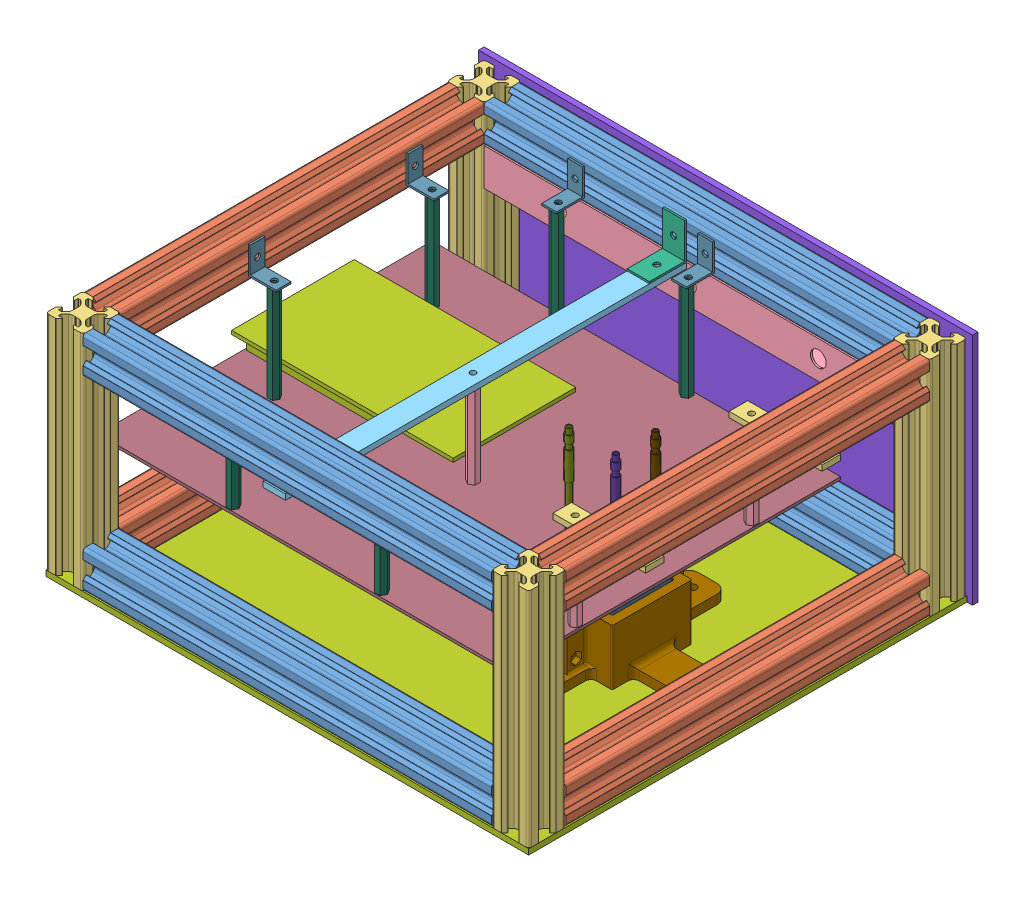
SolidWorks assembly Электродный блок, configuration По умолчанию. Lengths in mm.
Overall size (266 126 239).
75 component instances, 36 part files, 131 mates.
Components (placement in the parent):
- профиль x1-1: профиль x1 [00] at (0 10 10) x (0 0 1) z (-1 0 0) size (20 20 220)
- профиль z1-1: профиль z1 [00] at (10 10 20) size (20 20 196)
- профиль y-1: профиль y [00] at (10 120 10) x (1 0 0) z (0 -1 0) size (20 20 120)
- уголок 8-1: уголок 8 [По умолчанию] at (-220 80 20) x (0 0 -1) z (0 -1 0) size (20 220 20)
- уголок 10-1: уголок 10 [По умолчанию] at (-220 81 19) size (20 19 19)
- уголок 11-2: уголок 11 [По умолчанию] at (0 81 19) x (0 0 -1) z (1 0 0) size (19 19 20)
- Крышка ЭБ-1: Крышка ЭБ [По умолчанию] at (-15.6691 90 -0.0645) size (260 3 236) (hidden)
- Днище ЭБ-1: Днище ЭБ [По умолчанию] at (-21.0208 0 19.9277) size (260 3 236)
- Передняя панель ЭБ-1: Передняя панель ЭБ [По умолчанию] at origin size (3 126 236) (hidden)
- Задняя панель ЭБ-1: Задняя панель ЭБ [По умолчанию] at origin size (3 126 236) (hidden)
- Левая панель ЭБ-1: Левая панель ЭБ [По умолчанию] at origin size (266 126 3)
- Правая панель ЭБ-1: Правая панель ЭБ [По умолчанию] at origin size (266 126 3) (hidden)
- профиль x1-6: профиль x1 [00] at (-220 10 226) x (0 0 -1) z (1 0 0) size (20 20 220)
- профиль y-5: профиль y [00] at (10 0 226) x (1 0 0) z (0 1 0) size (20 20 120)
- профиль z1-5: профиль z1 [00] at (-230 10 216) x (-1 0 0) z (0 0 -1) size (20 20 196)
- профиль y-6: профиль y [00] at (-230 120 226) x (-1 0 0) z (0 -1 0) size (20 20 120)
- профиль y-7: профиль y [00] at (-230 0 10) x (-1 0 0) z (0 1 0) size (20 20 120)
- профиль x1-7: профиль x1 [00] at (-220 110 10) x (0 0 1) z (1 0 0) size (20 20 220)
- профиль z1-6: профиль z1 [00] at (10 110 216) x (1 0 0) z (0 0 -1) size (20 20 196)
- профиль x1-8: профиль x1 [00] at (0 110 226) x (0 0 -1) z (-1 0 0) size (20 20 220)
- профиль z1-7: профиль z1 [00] at (-230 110 20) x (-1 0 0) z (0 0 1) size (20 20 196)
- Кювета с держателем-3: Кювета с держателем [Default] at (-69.5 5 134.5) x (1 0 0) z (0 1 0) size (74.5 103 46.5)
  - Держатель-1: Держатель [Default] at origin size (74.5 103 30)
  - Квадратная кювета-1: Квадратная кювета [Default] at (-0.25 33.25 0) x (0 -1 0) z (-1 0 0) size (33.5 39.5 33.5)
  - Зажим квадратный-1: Зажим квадратный [По умолчанию] at (-5 38 0) x (0 -1 0) z (-1 0 0) size (63 25 19.5)
  - Клипса-1: Клипса [Default] at origin size (7.5 15 10)
- Электродная плата-1: Электродная плата [Default] at (-240 48 208) size (220 12.5 180)
- Уголок крепления платы-1: Уголок крепления платы [По умолчанию] at (-174 102.5 20) x (0 1 0) z (1 0 0) size (15 15 8)
- Уголок крепления платы-2: Уголок крепления платы [По умолчанию] at (-104 102.5 20) x (0 1 0) z (1 0 0) size (15 15 8)
- Уголок крепления платы-3: Уголок крепления платы [По умолчанию] at (-220 102.5 62) x (0 1 0) z (0 0 -1) size (15 15 8)
- Стойка крепления платы-1: Стойка крепления платы [По умолчанию] at (-170 49.5 31) size (5 53 5.77)
- Стойка крепления платы-2: Стойка крепления платы [По умолчанию] at (-100 49.5 31) size (5 53 5.77)
- Стойка крепления платы-3: Стойка крепления платы [По умолчанию] at (-210 49.5 58) size (5 53 5.77)
- Крепление цанг-1: Крепление цанг [По умолчанию] at (0 65 143) x (-1 0 0) z (0 0 -1) size (75 55 50) (hidden)
- Цанга залив-1: Цанга залив [По умолчанию] at (-65.6 61.5 128.7) x (0.866025 0 -0.5) z (0.5 0 0.866025) size (12 60 13.86)
  - Цанговый зажим-1: Цанговый зажим [По умолчанию] at origin size (12 28.5 13.86)
    - втулка-1: втулка [По умолчанию] at origin size (9.5 23 9.5) (hidden)
    - цанга-1: цанга [По умолчанию] at (0 13 0) size (6 15.5 6) (hidden)
    - прижимная гайка-1: прижимная гайка [По умолчанию] at (0 16.5 0) x (-1 0 0) z (0 0 -1) size (11 10.5 11) (hidden)
    - фиксирующая гайка-1: фиксирующая гайка [По умолчанию] at (0 11.5 0) x (1 0 0) z (0 -1 0) size (12 13.86 2) (hidden)
  - Игла залив-1: Игла залив [По умолчанию] at (0 -21 0) size (4 60 4)
- Цанга забор-1: Цанга забор [По умолчанию] at (-40.4 61.5 128.7) size (12 72 13.86)
  - Цанговый зажим-1: Цанговый зажим [По умолчанию] at origin size (12 28.5 13.86)
    - втулка-1: втулка [По умолчанию] at origin size (9.5 23 9.5) (hidden)
    - цанга-1: цанга [По умолчанию] at (0 13 0) size (6 15.5 6) (hidden)
    - прижимная гайка-1: прижимная гайка [По умолчанию] at (0 16.5 0) x (-1 0 0) z (0 0 -1) size (11 10.5 11) (hidden)
    - фиксирующая гайка-1: фиксирующая гайка [По умолчанию] at (0 11.5 0) x (1 0 0) z (0 -1 0) size (12 13.86 2) (hidden)
  - Игла забор-1: Игла забор [По умолчанию] at (0 -33 0) size (4 72 4)
- Цанга слив-1: Цанга слив [По умолчанию] at (-40.4 61.5 107.3) size (12 92 13.86)
  - Цанговый зажим-1: Цанговый зажим [По умолчанию] at origin size (12 28.5 13.86)
    - втулка-1: втулка [По умолчанию] at origin size (9.5 23 9.5) (hidden)
    - цанга-1: цанга [По умолчанию] at (0 13 0) size (6 15.5 6) (hidden)
    - прижимная гайка-1: прижимная гайка [По умолчанию] at (0 16.5 0) x (-1 0 0) z (0 0 -1) size (11 10.5 11) (hidden)
    - фиксирующая гайка-1: фиксирующая гайка [По умолчанию] at (0 11.5 0) x (1 0 0) z (0 -1 0) size (12 13.86 2) (hidden)
  - Игла слив1-1: Игла слив1 [По умолчанию] at (0 -53 0) size (4 92 4)
- Электрод-фольга-1: Электрод-фольга [Default] at (-68.25 9 131.75) size (28 39 0.3)
- Электрод-фольга-2: Электрод-фольга [Default] at (-40.25 9 104.25) x (-1 0 0) z (0 0 -1) size (28 39 0.3)
- Иголка-электрод-1: Иголка-электрод [Default] at (-53.25 8.5 125) x (-0.595798 0 0.803134) z (-0.803134 0 -0.595798) size (1.5 39.5 1.5)
- Иголка-электрод-2: Иголка-электрод [Default] at (-53.25 8.5 111) x (-0.595798 0 -0.803134) z (0.803134 0 -0.595798) size (1.5 39.5 1.5)
- Стойка крепления платы-7: Стойка крепления платы [По умолчанию] at (-210 49.5 143) x (0 0 -1) z (1 0 0) size (5 53 5.77)
- Стойка крепления платы-8: Стойка крепления платы [По умолчанию] at (-170 49.5 205) x (0 0 -1) z (1 0 0) size (5 53 5.77)
- Стойка крепления платы-9: Стойка крепления платы [По умолчанию] at (-90 49.5 205) x (0.866025 0 -0.5) z (0.5 0 0.866025) size (5 53 5.77)
- Уголок крепления платы-7: Уголок крепления платы [По умолчанию] at (-220 102.5 147) x (0 1 0) z (0 0 -1) size (15 15 8)
- Уголок крепления платы-8: Уголок крепления платы [По умолчанию] at (-166 102.5 216) x (0 1 0) z (-1 0 0) size (15 15 8)
- Уголок крепления платы-9: Уголок крепления платы [По умолчанию] at (-86 102.5 216) x (0 1 0) z (-1 0 0) size (15 15 8)
- Пластина крпления платы-1: Пластина крпления платы [Default] at (-30 97 78) size (50 3 10)
- Пластина крпления платы-2: Пластина крпления платы [Default] at (-30 97 173) size (50 3 10)
- Стойка крепления платы средняя-1: Стойка крепления платы средняя [По умолчанию] at (-23 49.5 73) size (5 47.5 5.77)
- Стойка крепления платы средняя-2: Стойка крепления платы средняя [По умолчанию] at (-23 49.5 168) size (5 47.5 5.77)
- Пластина крепления центральная-1: Пластина крепления центральная [Default] at (-111 100 20) x (0 0 1) z (0 -1 0) size (216 12 3)
- Уголок крепления 20-1: Уголок крепления 20 [Default] at (-111 100 20) x (0 0 1) z (-1 0 0) size (20 20 12)
- Стойка крепления платы средняя-3: Стойка крепления платы средняя [По умолчанию] at (-117 49.5 129) size (5 47.5 5.77)
- юзб_блок-1: юзб_блок [По умолчанию] at (-240 59.8 136) size (119.3 12.3 66)
- Part2^Электродный блок-1: Part2^Электродный блок [Default] at origin size (65.25 29.5 48.5) (hidden, virtual)
- Part3^Электродный блок-1: Part3^Электродный блок [Default] at origin size (45.7 10.75 39.9) (hidden, virtual)
Mates (geometry in assembly coordinates):
- Совпадение20: coincident anti-aligned: plane of профиль x1-1 through (-220 18.5 0) normal (0 0 -1); plane of assembly through (0 0 0) normal (0 0 1)
- Совпадение21: coincident anti-aligned: plane of профиль x1-1 through (-220 0 1.5) normal (0 -1 0); plane of assembly through (0 0 0) normal (0 1 0)
- Совпадение22: coincident aligned: plane of профиль x1-1 through (0 10.3377 6.25) normal (1 0 0); plane of assembly through (0 0 0) normal (1 0 0)
- Совпадение23: coincident anti-aligned: plane of профиль x1-1 through (0 10.3377 6.25) normal (1 0 0); plane of профиль y-1 through (0 0 5.17) normal (-1 0 0)
- Совпадение24: coincident aligned: plane of профиль x1-1 through (-220 18.5 0) normal (0 0 -1); plane of профиль y-1 through (1.5 0 0) normal (0 0 -1)
- Совпадение25: coincident aligned: plane of профиль x1-1 through (-220 0 1.5) normal (0 -1 0); plane of профиль y-1 through (6.25 0 10.3377) normal (0 -1 0)
- Совпадение26: coincident aligned: plane of профиль z1-1 through (20 1.5 216) normal (1 0 0); plane of профиль y-1 through (20 0 1.5) normal (1 0 0)
- Совпадение27: coincident anti-aligned: plane of профиль z1-1 through (6.25 10.3377 20) normal (0 0 -1); plane of профиль y-1 through (18.5 0 20) normal (0 0 1)
- Совпадение28: coincident aligned: plane of профиль z1-1 through (14.83 0 216) normal (0 -1 0); plane of профиль y-1 through (6.25 0 10.3377) normal (0 -1 0)
- Совпадение62: coincident anti-aligned: plane of профиль y-1 through (0 0 18.5) normal (-1 0 0); plane of уголок 8-1 through (0 80 20) normal (1 0 0)
- Совпадение66: coincident anti-aligned: plane of уголок 8-1 through (0 81 19) normal (0 1 0); plane of уголок 10-1 through (-220 81 19) normal (0 -1 0)
- Совпадение67: coincident anti-aligned: plane of уголок 8-1 through (0 100 19) normal (0 0 -1); plane of уголок 10-1 through (-200 100 19) normal (0 0 1)
- Совпадение68: coincident anti-aligned: plane of уголок 8-1 through (0 100 19) normal (0 0 -1); plane of уголок 11-2 through (0 100 19) normal (0 0 1)
- Совпадение69: coincident anti-aligned: plane of профиль y-1 through (0 0 5.17) normal (-1 0 0); plane of уголок 11-2 through (0 100 -1) normal (1 0 0)
- Совпадение70: coincident anti-aligned: plane of уголок 8-1 through (0 81 19) normal (0 1 0); plane of уголок 11-2 through (0 81 19) normal (0 -1 0)
- Совпадение74: coincident anti-aligned: plane of профиль x1-1 through (-220 0 1.5) normal (0 -1 0); plane of Днище ЭБ-1 through (-21.0208 0 19.9277) normal (0 1 0)
- Совпадение77: coincident aligned: plane of профиль y-6 through (-234.83 0 236) normal (0 0 1); plane of Передняя панель ЭБ-1 through (-243 123 236) normal (0 0 1)
- Совпадение78: coincident aligned: plane of Крышка ЭБ-1 through (-15.6691 123 -0.0645) normal (0 1 0); plane of Передняя панель ЭБ-1 through (-243 123 0) normal (0 1 0)
- Совпадение79: coincident anti-aligned: plane of профиль y-6 through (-240 0 234.5) normal (-1 0 0); plane of Передняя панель ЭБ-1 through (-240 0 0) normal (1 0 0)
- Совпадение81: coincident aligned: plane of Крышка ЭБ-1 through (-15.6691 123 -0.0645) normal (0 1 0); plane of Задняя панель ЭБ-1 through (23 123 0) normal (0 1 0)
- Совпадение83: coincident aligned: plane of Передняя панель ЭБ-1 through (-243 0 0) normal (-1 0 0); plane of Левая панель ЭБ-1 through (-243 123 -3) normal (-1 0 0)
- Совпадение84: coincident aligned: plane of Крышка ЭБ-1 through (-15.6691 123 -0.0645) normal (0 1 0); plane of Левая панель ЭБ-1 through (23 123 -3) normal (0 1 0)
- Совпадение86: coincident aligned: plane of Крышка ЭБ-1 through (-15.6691 123 -0.0645) normal (0 1 0); plane of Правая панель ЭБ-1 through (23 123 239) normal (0 1 0)
- Совпадение87: coincident aligned: plane of Задняя панель ЭБ-1 through (23 0 0) normal (1 0 0); plane of Правая панель ЭБ-1 through (23 -3 239) normal (1 0 0)
- Coincident28: coincident aligned: plane of профиль y-1 through (1.5 0 0) normal (0 0 -1); plane of уголок 8-1 through (0 81 0) normal (0 0 -1)
- Coincident29: coincident anti-aligned: plane of профиль y-7 through (-220 120 5.17) normal (1 0 0); plane of уголок 10-1 through (-220 100 19) normal (-1 0 0)
- Coincident32: coincident aligned: plane of профиль y-1 through (20 0 1.5) normal (1 0 0); plane of Крышка ЭБ-1 through (20 123 0) normal (1 0 0)
- Coincident33: coincident aligned: plane of профиль y-1 through (14.83 0 0) normal (0 0 -1); plane of Крышка ЭБ-1 through (-240 123 0) normal (0 0 -1)
- Coincident34: coincident anti-aligned: plane of профиль y-1 through (6.25 120 10.3377) normal (0 1 0); plane of Крышка ЭБ-1 through (-15.6691 120 -0.0645) normal (0 -1 0)
- Coincident35: coincident aligned: plane of профиль y-1 through (14.83 0 0) normal (0 0 -1); plane of Днище ЭБ-1 through (-240 -3 0) normal (0 0 -1)
- Coincident36: coincident aligned: plane of профиль y-1 through (20 0 1.5) normal (1 0 0); plane of Днище ЭБ-1 through (20 -3 0) normal (1 0 0)
- Coincident37: coincident aligned: plane of профиль y-7 through (-234.83 120 0) normal (0 0 -1); plane of Передняя панель ЭБ-1 through (-243 123 0) normal (0 0 -1)
- Coincident38: coincident aligned: plane of Крышка ЭБ-1 through (-15.6691 123 -0.0645) normal (0 1 0); plane of Передняя панель ЭБ-1 through (-243 123 0) normal (0 1 0)
- Coincident39: coincident aligned: plane of Крышка ЭБ-1 through (-15.6691 123 -0.0645) normal (0 1 0); plane of Задняя панель ЭБ-1 through (23 123 0) normal (0 1 0)
- Coincident40: coincident aligned: plane of профиль y-1 through (14.83 0 0) normal (0 0 -1); plane of Задняя панель ЭБ-1 through (23 -3 0) normal (0 0 -1)
- Coincident41: coincident anti-aligned: plane of профиль y-1 through (20 0 1.5) normal (1 0 0); plane of Задняя панель ЭБ-1 through (20 0 0) normal (-1 0 0)
- Coincident42: coincident aligned: plane of Крышка ЭБ-1 through (-15.6691 123 -0.0645) normal (0 1 0); plane of Левая панель ЭБ-1 through (23 123 -3) normal (0 1 0)
- Coincident43: coincident aligned: plane of Задняя панель ЭБ-1 through (23 0 0) normal (1 0 0); plane of Левая панель ЭБ-1 through (23 123 -3) normal (1 0 0)
- Coincident44: coincident aligned: plane of Задняя панель ЭБ-1 through (23 -3 236) normal (0 -1 0); plane of Левая панель ЭБ-1 through (23 -3 -3) normal (0 -1 0)
- Coincident45: coincident anti-aligned: plane of профиль y-7 through (-221.5 120 0) normal (0 0 -1); plane of Левая панель ЭБ-1 through (0 0 0) normal (0 0 1)
- Coincident46: coincident aligned: plane of Крышка ЭБ-1 through (-15.6691 123 -0.0645) normal (0 1 0); plane of Правая панель ЭБ-1 through (23 123 239) normal (0 1 0)
- Coincident47: coincident aligned: plane of Передняя панель ЭБ-1 through (-243 0 0) normal (-1 0 0); plane of Правая панель ЭБ-1 through (-243 123 239) normal (-1 0 0)
- Coincident48: coincident anti-aligned: plane of профиль y-6 through (-234.83 0 236) normal (0 0 1); plane of Правая панель ЭБ-1 through (0 0 236) normal (0 0 -1)
- Coincident49: coincident anti-aligned: plane of уголок 8-1 through (0 100 20) normal (0 1 0); plane of профиль x1-7 through (0 100 18.5) normal (0 -1 0)
- Coincident50: coincident anti-aligned: plane of уголок 10-1 through (-220 100 19) normal (-1 0 0); plane of профиль y-7 through (-220 120 5.17) normal (1 0 0)
- Coincident51: coincident aligned: plane of Передняя панель ЭБ-1 through (-243 123 0) normal (0 0 -1); plane of профиль y-7 through (-234.83 120 0) normal (0 0 -1)
- Coincident52: coincident anti-aligned: plane of Левая панель ЭБ-1 through (0 0 0) normal (0 0 1); plane of профиль y-7 through (-234.83 120 0) normal (0 0 -1)
- Coincident53: coincident anti-aligned: plane of Правая панель ЭБ-1 through (0 0 236) normal (0 0 -1); plane of профиль y-6 through (-221.5 0 236) normal (0 0 1)
- Coincident58: coincident anti-aligned: plane of Днище ЭБ-1 through (-21.0208 0 19.9277) normal (0 1 0); plane of Кювета с держателем-3/Держатель-1 through (-69.5 0 134.5) normal (0 -1 0)
- Parallel1: parallel aligned: plane of профиль z1-7 through (-234.83 120 216) normal (0 1 0); plane of Электродная плата-1 through (-240 49.5 208) normal (0 1 0)
- Coincident60: coincident: plane of Электродная плата-1 through (-240 49.5 208) normal (0 1 0); line of assembly
- Coincident61: coincident aligned: plane of Кювета с держателем-3/Держатель-1 through (-69.5 5 118) normal (0 0 1); plane of Электродная плата-1 through (-240 48 118) normal (0 0 1)
- Coincident63: coincident aligned: plane of профиль y-7 through (-240 120 14.83) normal (-1 0 0); plane of Электродная плата-1 through (-240 49.5 208) normal (-1 0 0)
- Совпадение88: coincident anti-aligned: plane of профиль x1-7 through (0 118.5 20) normal (0 0 1); plane of Уголок крепления платы-1 through (-166 102.5 20) normal (0 0 -1)
- Совпадение89: coincident aligned: line of Уголок крепления платы-1 through (-170 117.5 20) axis (0 -1 0); line of assembly
- Совпадение91: coincident anti-aligned: plane of профиль x1-7 through (0 118.5 20) normal (0 0 1); plane of Уголок крепления платы-2 through (-96 102.5 20) normal (0 0 -1)
- Совпадение92: coincident aligned: line of Уголок крепления платы-2 through (-100 117.5 20) axis (0 -1 0); line of assembly
- Совпадение94: coincident aligned: line of Уголок крепления платы-3 through (-220 117.5 58) axis (0 -1 0); line of assembly
- Совпадение96: coincident anti-aligned: plane of профиль z1-7 through (-220 114.83 216) normal (1 0 0); plane of Уголок крепления платы-3 through (-220 102.5 54) normal (-1 0 0)
- Параллельность1: parallel aligned: plane of профиль z1-7 through (-220 101.5 216) normal (1 0 0); plane of Стойка крепления платы-1 through (-167.5 102.5 32.4434) normal (1 0 0)
- Совпадение97: coincident anti-aligned: plane of Электродная плата-1 through (-240 49.5 208) normal (0 1 0); plane of Стойка крепления платы-1 through (-170 49.5 31) normal (0 -1 0)
- Концентричный1: concentric aligned: cylinder of Электродная плата-1 through (-170 49.5 31) axis (0 -1 0) radius 1.55; cylinder of Стойка крепления платы-1 through (-170 102.5 31) axis (0 -1 0) radius 1.55
- Параллельность2: parallel aligned: plane of Уголок крепления платы-2 through (-96 102.5 20) normal (1 0 0); plane of Стойка крепления платы-2 through (-97.5 102.5 32.4434) normal (1 0 0)
- Совпадение98: coincident anti-aligned: plane of Электродная плата-1 through (-240 49.5 208) normal (0 1 0); plane of Стойка крепления платы-2 through (-100 49.5 31) normal (0 -1 0)
- Концентричный2: concentric aligned: cylinder of Электродная плата-1 through (-100 49.5 31) axis (0 -1 0) radius 1.55; cylinder of Стойка крепления платы-2 through (-100 102.5 31) axis (0 -1 0) radius 1.55
- Параллельность3: parallel aligned: plane of профиль z1-7 through (-220 114.83 216) normal (1 0 0); plane of Стойка крепления платы-3 through (-207.5 102.5 59.4434) normal (1 0 0)
- Совпадение99: coincident anti-aligned: plane of Электродная плата-1 through (-240 49.5 208) normal (0 1 0); plane of Стойка крепления платы-3 through (-210 49.5 58) normal (0 -1 0)
- Концентричный3: concentric aligned: cylinder of Электродная плата-1 through (-210 49.5 58) axis (0 -1 0) radius 1.55; cylinder of Стойка крепления платы-3 through (-210 102.5 58) axis (0 -1 0) radius 1.55
- Совпадение100: coincident: plane of Кювета с держателем-3/Держатель-1 through (-69.5 5 118) normal (0 0 1); line of Крепление цанг-1 through (0 120 118) axis (0 -1 0)
- Совпадение101: coincident anti-aligned: plane of профиль z1-6 through (0 101.5 20) normal (-1 0 0); plane of Крепление цанг-1 through (0 120 93) normal (1 0 0)
- Совпадение102: coincident aligned: plane of профиль z1-6 through (1.5 120 20) normal (0 1 0); plane of Крепление цанг-1 through (-3 120 93) normal (0 1 0)
- Параллельность4: parallel aligned: plane of Крепление цанг-1 through (0 65 143) normal (0 0 1); plane of Цанга залив-1/Цанговый зажим-1/фиксирующая гайка-1 through (-62.1359 71 134.7) normal (0 0 1)
- Параллельность7: parallel aligned: plane of Крепление цанг-1 through (-75 65 93) normal (-1 0 0); plane of Цанга забор-1/Цанговый зажим-1/фиксирующая гайка-1 through (-46.4 71 132.1641) normal (-1 0 0)
- Параллельность8: parallel aligned: plane of Крепление цанг-1 through (-75 65 93) normal (-1 0 0); plane of Цанга слив-1/Цанговый зажим-1/фиксирующая гайка-1 through (-46.4 71 110.7641) normal (-1 0 0)
- Concentric5: concentric anti-aligned: cylinder of Крепление цанг-1 through (-65.6 65 128.7) axis (0 1 0) radius 4; cylinder of Цанга залив-1/Цанговый зажим-1/втулка-1 through (-65.6 61.5 128.7) axis (0 -1 0) radius 3.75
- Concentric6: concentric anti-aligned: cylinder of Крепление цанг-1 through (-40.4 65 128.7) axis (0 1 0) radius 4; cylinder of Цанга забор-1/Цанговый зажим-1/втулка-1 through (-40.4 61.5 128.7) axis (0 -1 0) radius 3.75
- Concentric7: concentric anti-aligned: cylinder of Крепление цанг-1 through (-40.4 65 107.3) axis (0 1 0) radius 4; cylinder of Цанга слив-1/Цанговый зажим-1/втулка-1 through (-40.4 61.5 107.3) axis (0 -1 0) radius 3.75
- Coincident67: coincident anti-aligned: plane of Электродная плата-1 through (-240 48 208) normal (0 -1 0); plane of Электрод-фольга-1 through (-68.25 48 132.05) normal (0 1 0)
- Coincident69: coincident anti-aligned: plane of Электродная плата-1 through (-66.75 48 131.75) normal (0 0 1); plane of Электрод-фольга-1 through (-68.25 9 131.75) normal (0 0 -1)
- Coincident70: coincident anti-aligned: plane of Электродная плата-1 through (-240 48 208) normal (0 -1 0); plane of Иголка-электрод-1 through (-53.25 48 125) normal (0 1 0)
- Concentric9: concentric aligned: cylinder of Электродная плата-1 through (-210 49.5 143) axis (0 -1 0) radius 1.55; cylinder of Стойка крепления платы-7 through (-210 102.5 143) axis (0 -1 0) radius 1.55
- Coincident71: coincident anti-aligned: plane of Электродная плата-1 through (-240 49.5 208) normal (0 1 0); plane of Стойка крепления платы-7 through (-210 49.5 143) normal (0 -1 0)
- Coincident72: coincident anti-aligned: plane of Электродная плата-1 through (-240 49.5 208) normal (0 1 0); plane of Стойка крепления платы-8 through (-170 49.5 205) normal (0 -1 0)
- Concentric10: concentric aligned: cylinder of Электродная плата-1 through (-170 49.5 205) axis (0 -1 0) radius 1.55; cylinder of Стойка крепления платы-8 through (-170 102.5 205) axis (0 -1 0) radius 1.55
- Parallel2: parallel anti-aligned: plane of профиль x1-8 through (-220 101.5 236) normal (0 0 1); plane of Стойка крепления платы-8 through (-168.5566 102.5 202.5) normal (0 0 -1)
- Parallel3: parallel aligned: plane of профиль x1-8 through (-220 114.83 236) normal (0 0 1); plane of Стойка крепления платы-7 through (-211.4434 102.5 145.5) normal (0 0 1)
- Coincident73: coincident aligned: plane of Уголок крепления платы-1 through (-166 117.5 20) normal (0 1 0); plane of assembly through (0 117.5 0) normal (0 1 0)
- Coincident74: coincident aligned: plane of Уголок крепления платы-2 through (-96 117.5 20) normal (0 1 0); plane of assembly through (0 117.5 0) normal (0 1 0)
- Coincident75: coincident aligned: plane of Уголок крепления платы-3 through (-220 117.5 54) normal (0 1 0); plane of assembly through (0 117.5 0) normal (0 1 0)
- Coincident76: coincident: plane of Электродная плата-1 through (-240 49.5 208) normal (0 1 0); line of Стойка крепления платы-9 through (-88.5566 49.5 202.5) axis (-1 0 0)
- Concentric11: concentric aligned: cylinder of Электродная плата-1 through (-90 49.5 205) axis (0 -1 0) radius 1.55; cylinder of Стойка крепления платы-9 through (-90 102.5 205) axis (0 -1 0) radius 1.55
- Parallel4: parallel aligned: plane of профиль x1-8 through (-220 105.17 216) normal (0 0 -1); plane of Стойка крепления платы-9 through (-88.5566 102.5 202.5) normal (0 0 -1)
- Coincident77: coincident aligned: line of Уголок крепления платы-7 through (-220 117.5 143) axis (0 -1 0); line of assembly
- Coincident78: coincident aligned: plane of Уголок крепления платы-7 through (-220 117.5 139) normal (0 1 0); plane of assembly through (0 117.5 0) normal (0 1 0)
- Coincident79: coincident anti-aligned: plane of профиль z1-7 through (-220 114.83 216) normal (1 0 0); plane of Уголок крепления платы-7 through (-220 102.5 139) normal (-1 0 0)
- Coincident80: coincident anti-aligned: plane of профиль x1-8 through (-220 118.5 216) normal (0 0 -1); plane of Уголок крепления платы-8 through (-174 102.5 216) normal (0 0 1)
- Coincident81: coincident aligned: line of Уголок крепления платы-8 through (-170 117.5 216) axis (0 -1 0)
- Coincident82: coincident aligned: plane of Уголок крепления платы-8 through (-174 117.5 216) normal (0 1 0); plane of assembly through (0 117.5 0) normal (0 1 0)
- Coincident83: coincident anti-aligned: plane of профиль x1-8 through (-220 105.17 216) normal (0 0 -1); plane of Уголок крепления платы-9 through (-94 102.5 216) normal (0 0 1)
- Coincident84: coincident aligned: line of Уголок крепления платы-9 through (-90 117.5 216) axis (0 -1 0)
- Coincident85: coincident aligned: plane of Уголок крепления платы-9 through (-94 117.5 216) normal (0 1 0); plane of assembly through (0 117.5 0) normal (0 1 0)
- Concentric12: concentric aligned: cylinder of Электродная плата-1 through (-23 49.5 73) axis (0 -1 0) radius 1.55; cylinder of Пластина крпления платы-1 through (-23 100 73) axis (0 -1 0) radius 1.6
- Coincident92: coincident anti-aligned: plane of профиль z1-6 through (18.5 100 20) normal (0 -1 0); plane of Пластина крпления платы-1 through (-30 100 78) normal (0 1 0)
- Parallel5: parallel aligned: plane of профиль z1-6 through (20 105.17 20) normal (1 0 0); plane of Пластина крпления платы-1 through (20 100 78) normal (1 0 0)
- Coincident93: coincident aligned: plane of профиль z1-6 through (20 105.17 20) normal (1 0 0); plane of Пластина крпления платы-1 through (20 100 78) normal (1 0 0)
- Coincident94: coincident anti-aligned: plane of профиль z1-6 through (18.5 100 20) normal (0 -1 0); plane of Пластина крпления платы-2 through (-30 100 173) normal (0 1 0)
- Concentric13: concentric aligned: cylinder of Электродная плата-1 through (-23 49.5 168) axis (0 -1 0) radius 1.55; cylinder of Пластина крпления платы-2 through (-23 100 168) axis (0 -1 0) radius 1.6
- Coincident95: coincident aligned: plane of профиль z1-6 through (20 105.17 20) normal (1 0 0); plane of Пластина крпления платы-2 through (20 100 173) normal (1 0 0)
- Concentric14: concentric aligned: cylinder of Электродная плата-1 through (-23 49.5 73) axis (0 -1 0) radius 1.55; cylinder of Стойка крепления платы средняя-1 through (-23 97 73) axis (0 -1 0) radius 1.5
- Coincident96: coincident: plane of Электродная плата-1 through (-240 49.5 208) normal (0 1 0); line of Стойка крепления платы средняя-1 through (-25.5 49.5 71.5566) axis (0 0 1)
- Parallel6: parallel aligned: plane of профиль z1-6 through (0 114.83 20) normal (-1 0 0); plane of Стойка крепления платы средняя-1 through (-25.5 97 71.5566) normal (-1 0 0)
- Concentric15: concentric aligned: cylinder of Электродная плата-1 through (-23 49.5 168) axis (0 -1 0) radius 1.55; cylinder of Стойка крепления платы средняя-2 through (-23 97 168) axis (0 -1 0) radius 1.5
- Coincident97: coincident: plane of Электродная плата-1 through (-240 49.5 208) normal (0 1 0); line of Стойка крепления платы средняя-2 through (-25.5 49.5 166.5566) axis (0 0 1)
- Parallel7: parallel aligned: plane of профиль z1-6 through (0 114.83 20) normal (-1 0 0); plane of Стойка крепления платы средняя-2 through (-25.5 97 166.5566) normal (-1 0 0)
- Coincident98: coincident: plane of Пластина крепления центральная-1; line of assembly
- Coincident99: coincident anti-aligned: plane of профиль x1-8 through (-220 100 230.83) normal (0 -1 0); plane of Пластина крепления центральная-1 through (-111 100 20) normal (0 1 0)
- Coincident100: coincident aligned: plane of профиль x1-8 through (-220 101.5 236) normal (0 0 1); plane of Пластина крепления центральная-1 through (-111 97 236) normal (0 0 1)
- Coincident101: coincident: plane of Пластина крепления центральная-1; line of Уголок крепления 20-1 through (-117 120 20) axis (0 -1 0)
- Coincident102: coincident anti-aligned: plane of профиль x1-7 through (0 105.17 20) normal (0 0 1); plane of Уголок крепления 20-1 through (-123 120 20) normal (0 0 -1)
- Coincident103: coincident aligned: plane of профиль x1-7 through (0 120 14.83) normal (0 1 0); plane of Уголок крепления 20-1 through (-123 120 21) normal (0 1 0)
- Concentric16: concentric anti-aligned: cylinder of Пластина крепления центральная-1 through (-117 97 129) axis (0 1 0) radius 1.55; cylinder of Стойка крепления платы средняя-3 through (-117 97 129) axis (0 -1 0) radius 1.5
- Coincident104: coincident: line of Пластина крепления центральная-1 through (-123 97 236) axis (0 0 -1); plane of Стойка крепления платы средняя-3 through (-117 97 129) normal (0 1 0)
- Parallel8: parallel aligned: plane of Пластина крепления центральная-1 through (-123 97 20) normal (-1 0 0); plane of Стойка крепления платы средняя-3 through (-119.5 97 127.5566) normal (-1 0 0)
- Совпадение105: coincident aligned: plane of Электродная плата-1 through (-240 49.5 208) normal (-1 0 0); plane of юзб_блок-1 through (-240 61.8 136) normal (-1 0 0)
- Совпадение106: coincident anti-aligned: plane of Электродная плата-1 through (-240 49.5 208) normal (0 1 0); plane of юзб_блок-1 through (-240 49.5 136) normal (0 -1 0)
- Coincident105: coincident: line of Электродная плата-1 through (-240 49.5 70) axis (1 0 0); plane of юзб_блок-1 through (-240 61.8 70) normal (0 0 -1)
- Coincident106: coincident anti-aligned: plane of Крепление цанг-1 through (0 65 93) normal (0 -1 0); plane of Цанга залив-1/Цанговый зажим-1/втулка-1 through (-62.3524 65 126.825) normal (0 1 0)
- Coincident107: coincident anti-aligned: plane of Крепление цанг-1 through (0 65 93) normal (0 -1 0); plane of Цанга слив-1/Цанговый зажим-1/втулка-1 through (-36.65 65 107.3) normal (0 1 0)
- Coincident108: coincident anti-aligned: plane of Крепление цанг-1 through (0 65 93) normal (0 -1 0); plane of Цанга забор-1/Цанговый зажим-1/втулка-1 through (-36.65 65 128.7) normal (0 1 0)
- Coincident109: coincident anti-aligned: plane of профиль z1-1 through (0 5.17 216) normal (-1 0 0); plane of Кювета с держателем-3/Держатель-1 through (0 5 134.5) normal (1 0 0)
- Concentric17: concentric anti-aligned: cylinder of Уголок крепления платы-3 through (-210 102.5 58) axis (0 1 0) radius 1.6; cylinder of Стойка крепления платы-3 through (-210 102.5 58) axis (0 -1 0) radius 1.55
